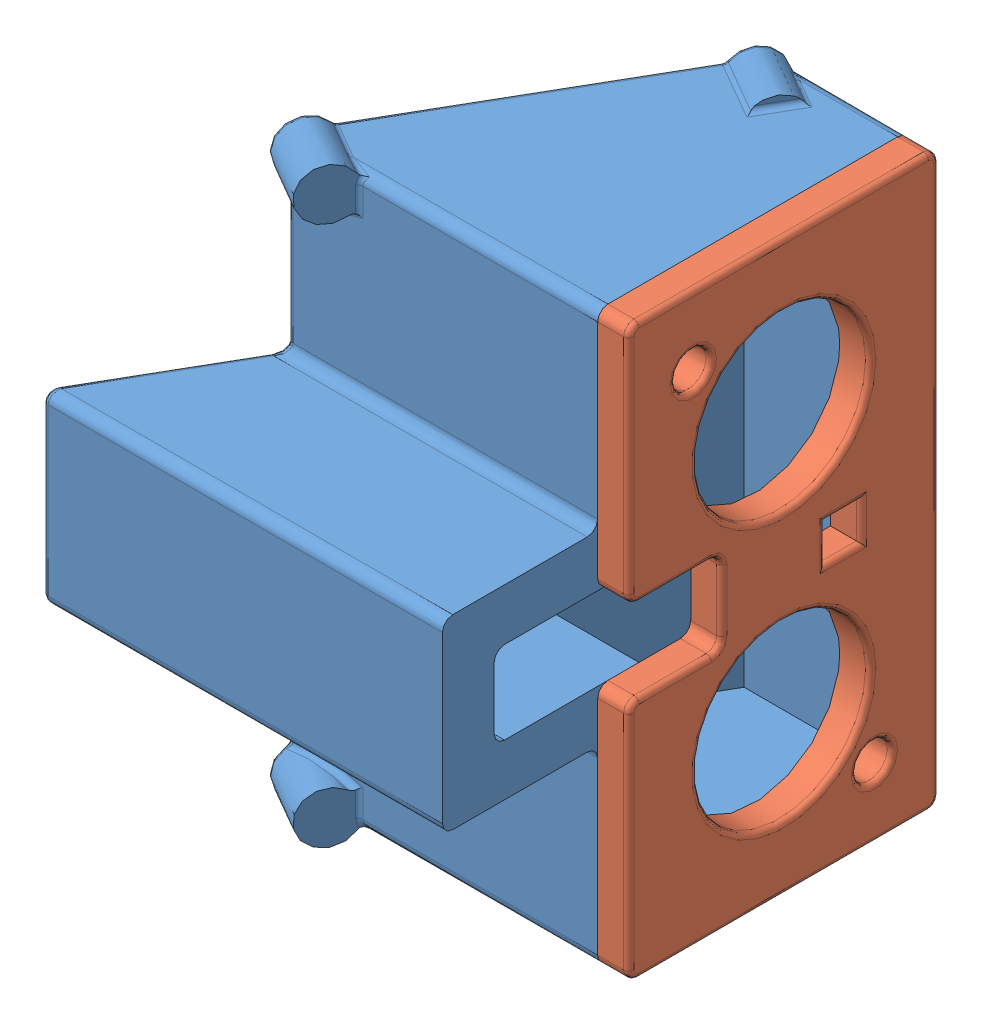
SolidWorks assembly SensorHolderAssembly, configuration Default. Lengths in mm.
Overall size (41.61 57.17 45.76).
2 component instances, 2 part files, 3 mates.
Components (placement in the parent):
- SensorHolderBack-1: SensorHolderBack [Default] at (-91.2605 -4.1774 13.7069) size (38.62 57.17 45.76)
- SensorHolderFront-1: SensorHolderFront [Default] at (-78.2605 23.3226 28.7069) x (0 -1 0) z (0 0 1) size (55 9.01 30)
Mates (geometry in assembly coordinates):
- Coincident1: coincident aligned: plane of SensorHolderBack-1 through (-78.2605 50.8226 13.7069) normal (0 0 -1); plane of SensorHolderFront-1 through (-75.2605 50.8226 13.7069) normal (0 0 -1)
- Coincident2: coincident aligned: plane of SensorHolderBack-1 through (-91.2605 -4.1774 13.7069) normal (0 -1 0); plane of SensorHolderFront-1 through (-75.2605 -4.1774 43.7069) normal (0 -1 0)
- Coincident4: coincident anti-aligned: plane of SensorHolderBack-1 through (-78.2605 50.8226 43.7069) normal (1 0 0); plane of SensorHolderFront-1 through (-78.2605 23.3226 28.7069) normal (-1 0 0)
